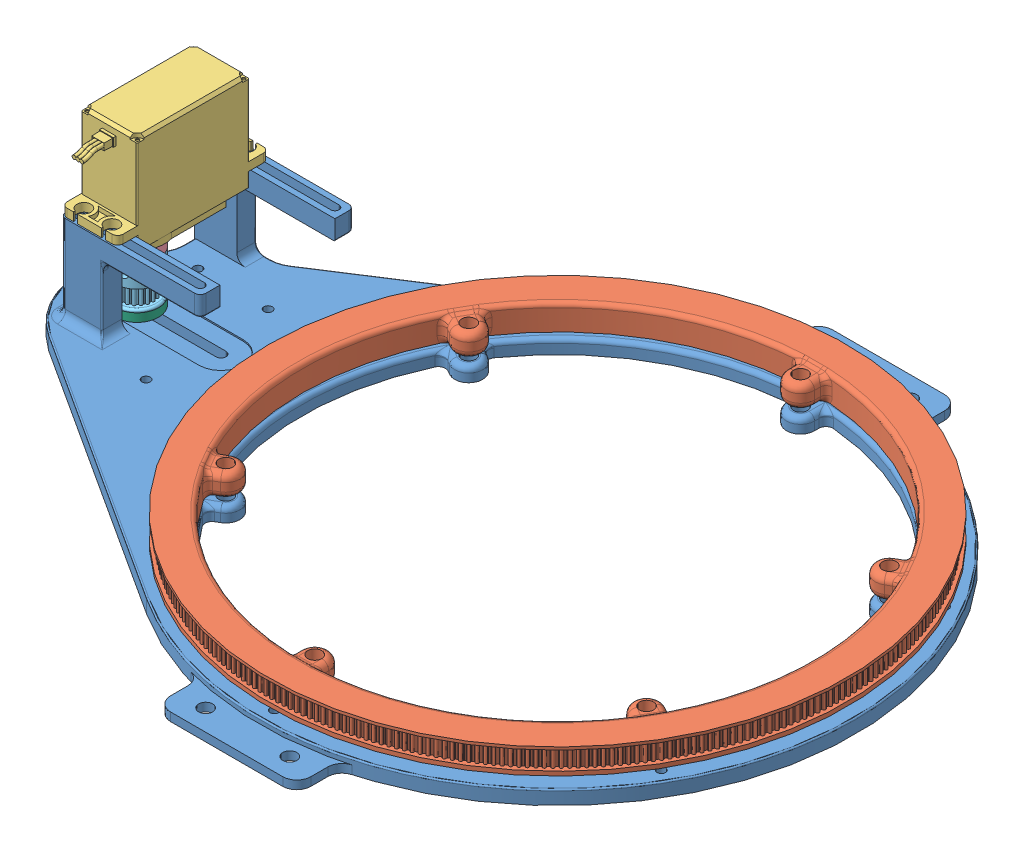
SolidWorks assembly Snare Type Payload Mechanism, configuration Varsayılan. Lengths in mm.
Overall size (294.21 66 248.42).
6 component instances, 6 part files, 11 mates.
Components (placement in the parent):
- sabit halka-1: sabit halka [Varsayılan] at (-7.3911 121.6814 232.1249) size (276 36 236.02)
- taşıyıcı halka-1: taşıyıcı halka [Varsayılan] at (-7.3911 128.6814 232.1249) x (0.233598 0 0.972333) z (-0.972333 0 0.233598) size (206 9.14 206)
- TP MG996R-1: TP MG996R [Default] at (-157.3911 187.6814 222.0307) x (0 0 1) z (1 0 0) size (58.18 41.75 20)
- donusturucu-1: donusturucu [Varsayılan] at (-157.3911 149.1814 232.1249) x (-0.837169 0 -0.546944) z (-0.546944 0 0.837169) size (15.5 9.5 15.5)
- GT2 20 5mm.catpart-2: GT2 20 5mm.catpart [Varsayılan] at (-157.3911 144.6814 232.1249) x (-0.942334 0 0.334673) z (0 -1 0) size (15.5 15.5 15.3)
- ayarlama başkanı-2: ayarlama başkanı [Varsayılan] at (-157.3911 126.3814 232.1249) x (-0.933851 0 -0.357662) z (0.357662 0 -0.933851) size (15.4 8 15.4)
Mates (geometry in assembly coordinates):
- Concentric1: concentric aligned: cylinder of sabit halka-1 through (-7.3911 126.6814 232.1249) axis (0 -1 0) radius 91; cylinder of taşıyıcı halka-1 through (-7.3911 136.6814 232.1249) axis (0 -1 0) radius 91
- Parallel1: parallel aligned: plane of TP MG996R-1 through (-147.3911 152.6814 202.0307) normal (1 0 0); plane of assembly through (0 0 0) normal (1 0 0)
- Coincident3: coincident anti-aligned: plane of sabit halka-1 through (-7.3911 134.6814 232.1249) normal (0 1 0); plane of taşıyıcı halka-1 through (-7.3911 134.6814 232.1249) normal (0 -1 0)
- Eş Merkezli1: concentric aligned: cylinder of TP MG996R-1 through (-157.3911 149.1814 232.1249) axis (0 1 0) radius 3.5; cylinder of donusturucu-1 through (-157.3911 145.6814 232.1249) axis (0 1 0) radius 3.1
- Çakışık1: coincident anti-aligned: plane of TP MG996R-1 through (-157.3911 149.1814 222.0307) normal (0 -1 0); plane of donusturucu-1 through (-157.3911 149.1814 232.1249) normal (0 1 0)
- Eş Merkezli2: concentric aligned: cylinder of donusturucu-1 through (-157.3911 139.6814 232.1249) axis (0 1 0) radius 2.35; cylinder of GT2 20 5mm.catpart-2 through (-157.3911 140.6814 232.1249) axis (0 1 0) radius 2.5
- Çakışık2: coincident anti-aligned: plane of donusturucu-1 through (-157.3911 144.6814 232.1249) normal (0 -1 0); plane of GT2 20 5mm.catpart-2 through (-157.3911 144.6814 232.1249) normal (0 1 0)
- Çakışık5: coincident anti-aligned: plane of sabit halka-1 through (-7.3911 157.6814 232.1249) normal (0 1 0); plane of TP MG996R-1 through (-167.3911 157.6814 195.0307) normal (0 -1 0)
- Eş Merkezli3: concentric anti-aligned: cylinder of GT2 20 5mm.catpart-2 through (-157.3911 140.6814 232.1249) axis (0 1 0) radius 2.5; cylinder of ayarlama başkanı-2 through (-157.3911 134.3814 232.1249) axis (0 -1 0) radius 2
- Çakışık7: coincident anti-aligned: plane of GT2 20 5mm.catpart-2 through (-157.3911 129.3814 232.1249) normal (0 -1 0); plane of ayarlama başkanı-2 through (-157.3911 129.3814 232.1249) normal (0 1 0)
- Slot4: slot anti-aligned: cylinder of ayarlama başkanı-2 through (-157.3911 129.3814 232.1249) axis (0 -1 0) radius 7.7; plane of sabit halka-1 through (-157.3911 126.1814 240.0249) normal (0 0 -1); cylinder of sabit halka-1 through (-127.3911 126.1814 232.1249) axis (0 1 0) radius 7.9
